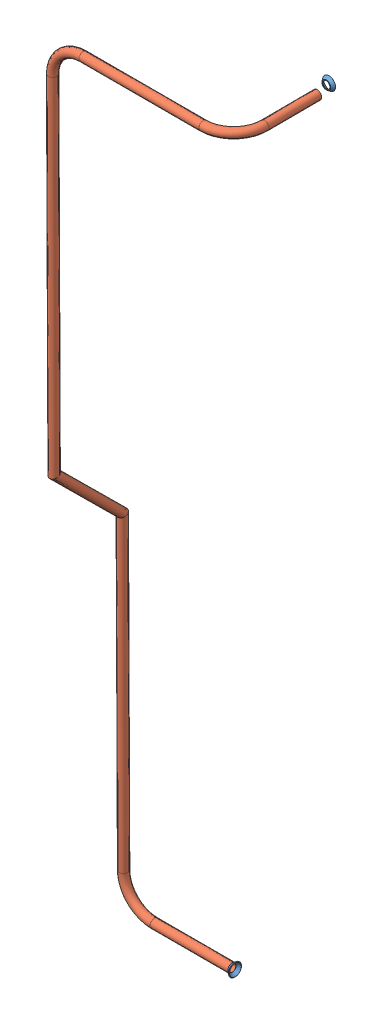
SolidWorks assembly Pipe 18, configuration Default. Lengths in mm.
Overall size (139.59 581.46 72.47).
3 component instances, 2 part files, 0 mates.
Components (placement in the parent):
- Flared pipe end - .25 inch-6: Flared pipe end - .25 inch [Default] at (-970.826 930.0401 552.7784) x (0 0.004278 -0.999991) z (1 0 0) size (9.41 9.41 2.36)
- Pipe 42-1: Pipe 42 [Default<As Machined>] at (50.0311 -411.1371 22.5271) x (1 0 0) z (0 -0.004278 0.999991) size (138.06 578.31 69.99)
- Flared pipe end - .25 inch-9: Flared pipe end - .25 inch [Default] at (-918.0313 1502.0663 537.4942) x (-1 0 0) z (0 0.004278 -0.999991) size (9.41 9.41 2.36)
